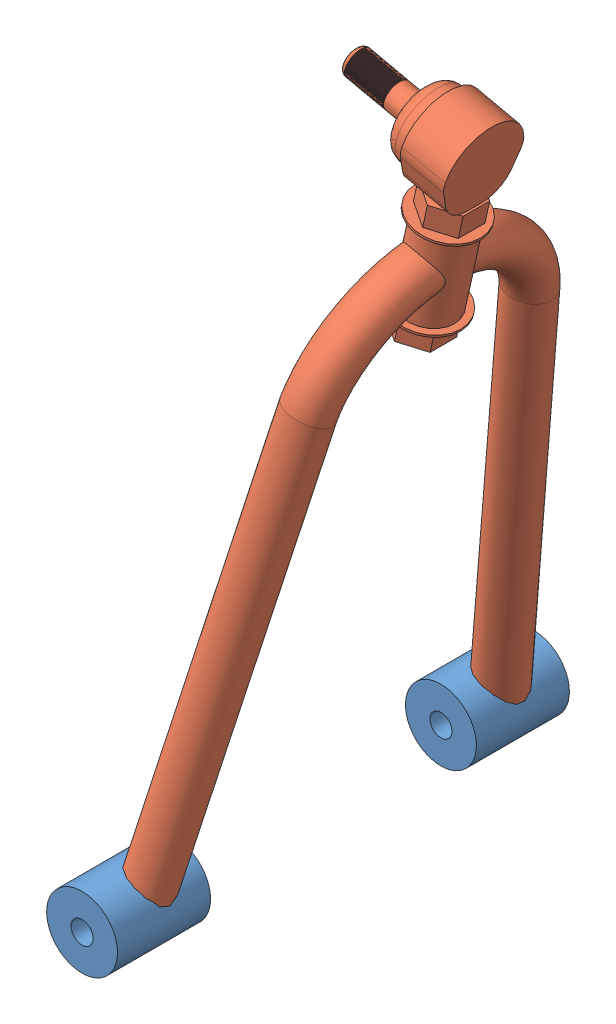
SolidWorks assembly Wahaczprawie, configuration Domyślna. Lengths in mm.
Overall size (134.31 338.84 204).
3 component instances, 2 part files, 3 mates.
Components (placement in the parent):
- Cz1dowahacza-1: Cz1dowahacza [Domyślna] at (-8.1871 4.0041 21) size (32 32 42)
- Cz1dowahacza-2: Cz1dowahacza [Domyślna] at (-8.1871 4.0041 -141) x (-0.761474 -0.648195 0) z (0 0 1) size (32 32 42)
- Cz2dowahacza-1: Cz2dowahacza [Domyślna] at (-3.3313 9.7326 -120.9563) x (0 0 1) z (-0.216037 -0.976385 0) size (194.28 67.36 317.28)
Mates (geometry in assembly coordinates):
- Odległość1: distance = 120 mm anti-aligned: plane of Cz1dowahacza-1 through (-8.1871 4.0041 21) normal (0 0 -1); plane of Cz1dowahacza-2 through (-8.1871 4.0041 -99) normal (0 0 1)
- Równolegle2: parallel aligned: cylinder of Cz1dowahacza-1 through (-8.1871 4.0041 63) axis (0 0 -1) radius 5; cylinder of Cz1dowahacza-2 through (-8.1871 4.0041 -99) axis (0 0 -1) radius 5
- Koncentryczne3: concentric aligned: cylinder of Cz1dowahacza-1 through (-8.1871 4.0041 63) axis (0 0 -1) radius 5; cylinder of Cz1dowahacza-2 through (-8.1871 4.0041 -99) axis (0 0 -1) radius 5
